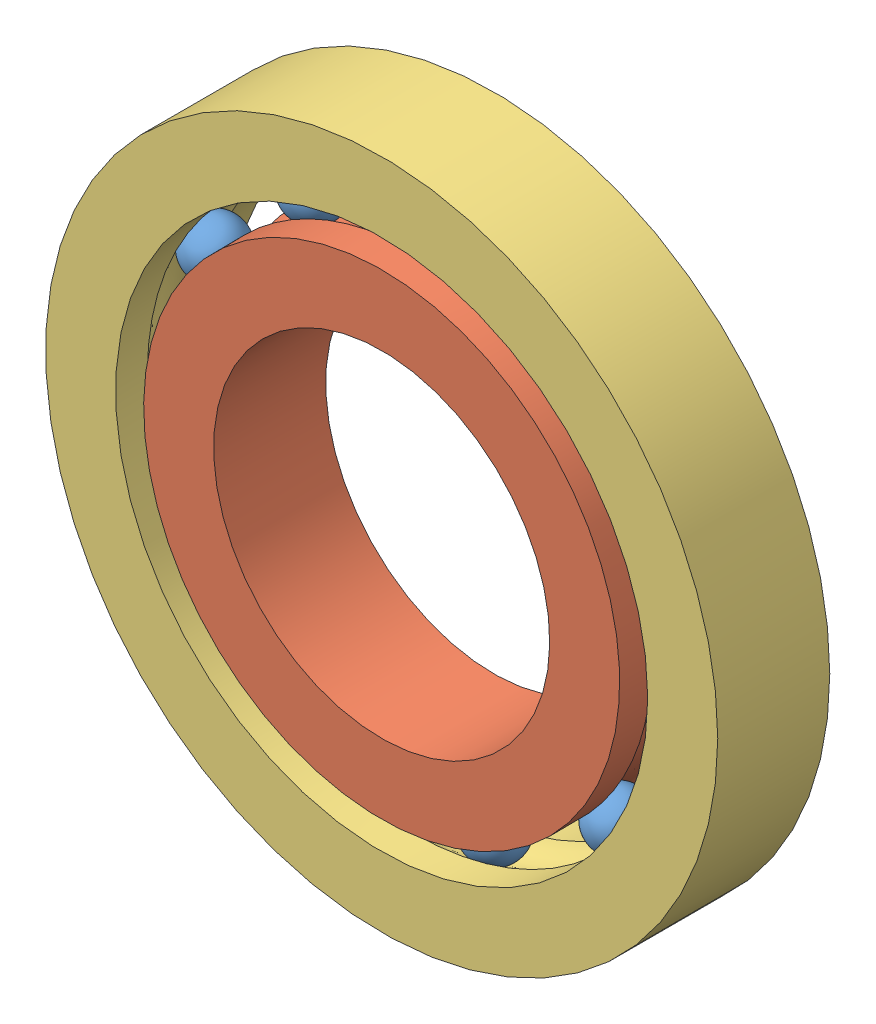
SolidWorks assembly Assem1, configuration Default. Lengths in mm.
Overall size (12 12 2).
13 component instances, 3 part files, 5 mates.
Components (placement in the parent):
- ball-1: ball [Default] at (14.0999 3.1642 -0.4212) x (0 0 -1) z (-0.361854 0.932235 0) size (1 1 1)
- inner-1: inner [Default] at (9.9049 1.5358 -0.4212) x (-0.361854 0.932235 0) z (0 0 1) size (8.5 8.5 2)
- outer-1: outer [Default] at (9.9049 1.5358 -0.4212) size (12 12 2)
- ball-2: ball [Default] at (12.5536 5.1737 -0.4212) x (0 0 -1) z (-0.808415 0.588613 0) size (1 1 1)
- ball-3: ball [Default] at (10.1664 6.0282 -0.4212) x (0 0 -1) z (-0.99831 0.058111 0) size (1 1 1)
- ball-4: ball [Default] at (7.6961 5.4564 -0.4212) x (0 0 -1) z (-0.871249 -0.490841 0) size (1 1 1)
- ball-5: ball [Default] at (5.9271 3.6399 -0.4212) x (0 0 -1) z (-0.467572 -0.883955 0) size (1 1 1)
- ball-6: ball [Default] at (5.421 1.1553 -0.4212) x (0 0 -1) z (0.084555 -0.996419 0) size (1 1 1)
- ball-7: ball [Default] at (6.3385 -1.2084 -0.4212) x (0 0 -1) z (0.609837 -0.792527 0) size (1 1 1)
- ball-8: ball [Default] at (8.3883 -2.7009 -0.4212) x (0 0 -1) z (0.9415 -0.337013 0) size (1 1 1)
- ball-9: ball [Default] at (10.9196 -2.8483 -0.4212) x (0 0 -1) z (0.974243 0.2255 0) size (1 1 1)
- ball-10: ball [Default] at (13.1288 -1.6037 -0.4212) x (0 0 -1) z (0.697671 0.716418 0) size (1 1 1)
- ball-11: ball [Default] at (14.3143 0.6376 -0.4212) x (0 0 -1) z (0.199593 0.979879 0) size (1 1 1)
Mates (geometry in assembly coordinates):
- Concentric1: concentric aligned: cylinder of inner-1 through (9.9049 1.5358 1.2311) axis (0 0 1) radius 3; cylinder of outer-1 through (9.9049 1.5358 3.346) axis (0 0 1) radius 4.75
- Coincident1: coincident aligned: plane of inner-1 through (9.9049 1.5358 -0.4212) normal (0 0 1); plane of outer-1 through (9.9049 1.5358 -0.4212) normal (0 0 1)
- Coincident3: coincident aligned: plane of ball-1 through (14.0999 3.1642 -0.4212) normal (-0.361854 0.932235 0); plane of inner-1 through (9.9049 1.5358 -0.4212) normal (-0.361854 0.932235 0)
- Coincident4: coincident anti-aligned: plane of ball-1 through (14.0999 3.1642 -0.4212) normal (0 0 -1); plane of inner-1 through (9.9049 1.5358 -0.4212) normal (0 0 1)
- Tangent2: tangent anti-aligned: sphere of ball-1; torus of inner-1
